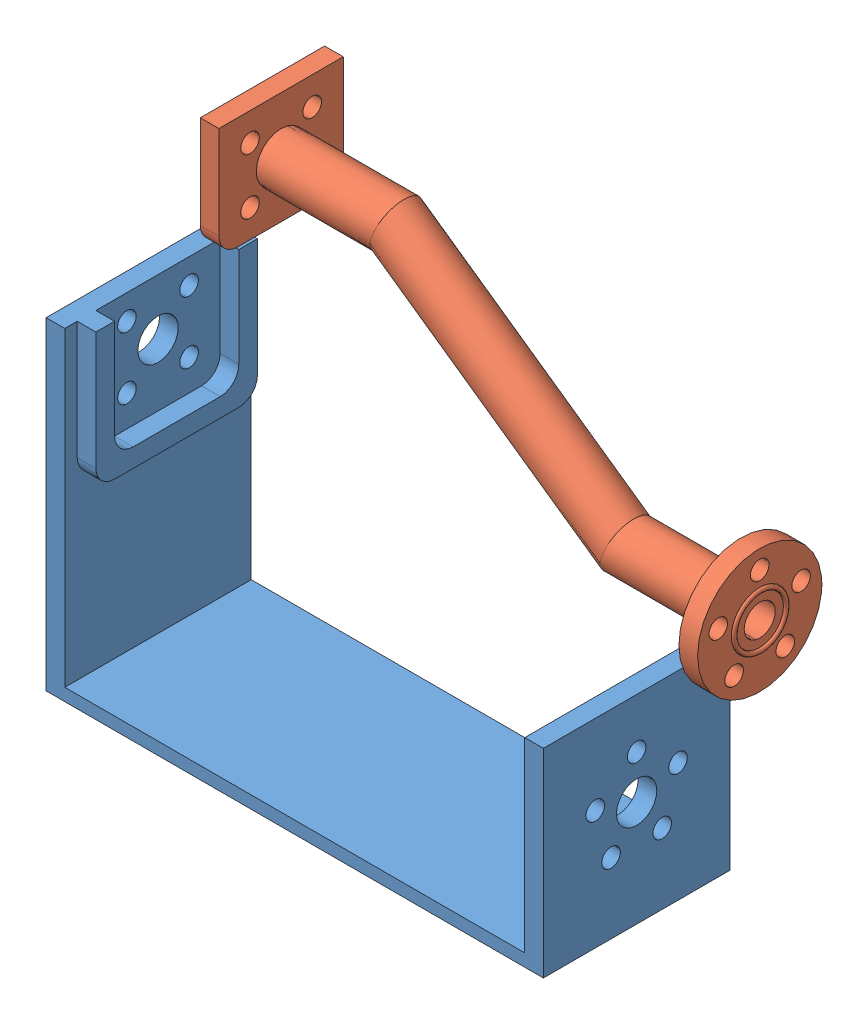
SolidWorks assembly Assem2, configuration Default. Lengths in mm.
Overall size (89.18 76.25 36).
2 component instances, 2 part files, 0 mates.
Components (placement in the parent):
- twoValves-1: twoValves [Default] at origin size (80 52 30)
- Part1-1: Part1 [Default] at (-28.198 67.2541 -11.0003) size (80.38 45 20)
